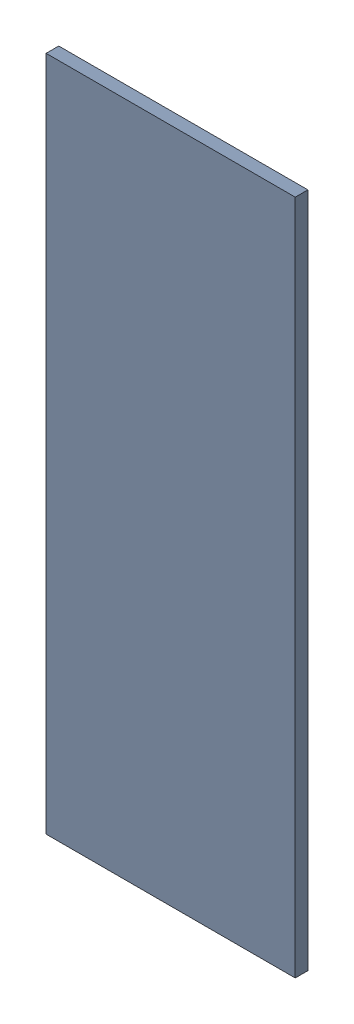
SolidWorks assembly Pad RAK4600-37(23.725mm,31.391mm) on Top Layer, configuration Predeterminado. Lengths in mm.
Overall size (0.7 1.9 0.04).
2 component instances, 1 part files, 0 mates.
Components (placement in the parent):
- Pad RAK4600-37(23.725mm,31.391mm) on Top Layer-1-1: Pad RAK4600-37(23.725mm,31.391mm) on Top Layer-1 [Predeterminado] at (-68.317 -44.187 -0.0457) size (0.7 1.9 0.04)
  - Pad RAK4600-37(23.725mm,31.391mm) on Top Layer-Part-1-1: Pad RAK4600-37(23.725mm,31.391mm) on Top Layer-Part-1 [Predeterminado] at origin size (0.7 1.9 0.04)
